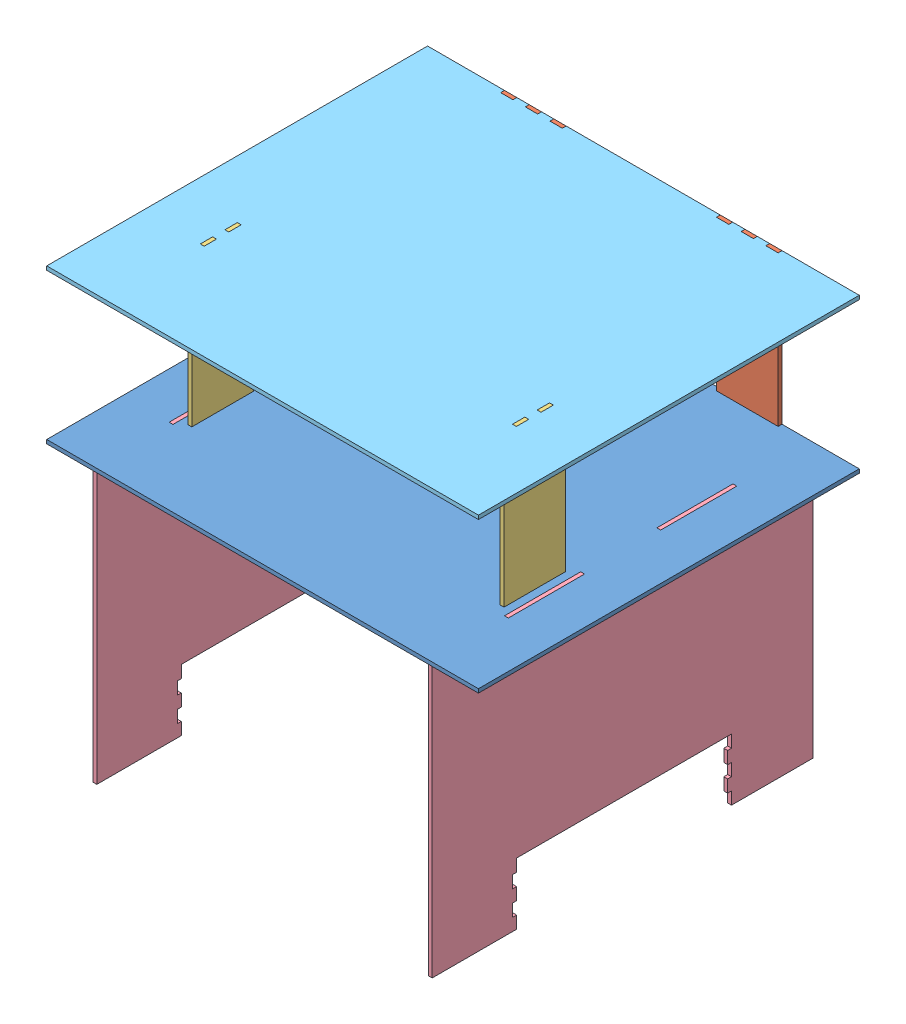
SolidWorks assembly Assem2, configuration Varsayılan. Lengths in mm.
Overall size (560 550 494).
8 component instances, 5 part files, 26 mates.
Components (placement in the parent):
- A_1-1: A_1 [Default] at (-17.2972 -28.734 560) size (560 5 494)
- D_1_prime-4: D_1_prime [Default] at (-157.5107 71.266 313) x (0 -1 0) z (-1 0 0) size (200 5 80)
- D_1_prime-5: D_1_prime [Default] at (122.4893 71.266 313) x (0 1 0) z (1 0 0) size (200 5 80)
- G_1_prime-1: G_1_prime [Default] at (-217.2972 98.766 658.801) x (0 1 0) z (0 0 1) size (200 5 80)
- G_1_prime-3: G_1_prime [Default] at (187.7028 98.766 658.801) x (0 1 0) z (0 0 1) size (200 5 80)
- B_1_prime-1: B_1_prime [Default] at (-237.2972 -306.234 560) size (5 355 494)
- B_1_prime-2: B_1_prime [Default] at (197.7028 -306.234 560) size (5 355 494)
- H_1-1: H_1 [Default] at (-17.2972 166.266 559.9971) size (560 5 494)
Mates (geometry in assembly coordinates):
- Coincident2: coincident aligned: plane of A_1-1 through (-17.2972 -28.734 560) normal (0 -1 0); plane of ? through (182.7028 -28.734 698.801) normal (0 -1 0)
- Coincident3: coincident anti-aligned: plane of A_1-1 through (182.7028 -23.734 634.801) normal (0 0 1); plane of ? through (182.7028 -28.734 634.801) normal (0 0 -1)
- Coincident4: coincident anti-aligned: plane of A_1-1 through (187.7028 -23.734 650.8019) normal (-1 0 0); plane of ? through (187.7028 71.266 674.801) normal (1 0 0)
- Coincident5: coincident aligned: plane of A_1-1 through (-17.2972 -28.734 560) normal (0 -1 0); plane of ? through (-222.2972 -28.734 734.3594) normal (0 -1 0)
- Coincident6: coincident anti-aligned: plane of A_1-1 through (-222.2972 -23.734 682.8038) normal (1 0 0); plane of ? through (-222.2972 71.266 710.3594) normal (-1 0 0)
- Coincident8: coincident anti-aligned: plane of A_1-1 through (-181.5107 -23.734 318) normal (0 0 -1); plane of D_1_prime-4 through (-157.5107 71.266 318) normal (0 0 1)
- Coincident9: coincident aligned: plane of A_1-1 through (-17.2972 -28.734 560) normal (0 -1 0); plane of D_1_prime-4 through (-117.5107 -28.734 318) normal (0 -1 0)
- Coincident10: coincident anti-aligned: plane of A_1-1 through (-117.5107 -23.734 318) normal (-1 0 0); plane of D_1_prime-4 through (-117.5107 171.266 318) normal (1 0 0)
- Coincident11: coincident anti-aligned: plane of A_1-1 through (82.4893 -23.734 318) normal (0 0 -1); plane of D_1_prime-5 through (122.4893 71.266 318) normal (0 0 1)
- Coincident12: coincident aligned: plane of A_1-1 through (-17.2972 -28.734 560) normal (0 -1 0); plane of D_1_prime-5 through (146.4893 -28.734 318) normal (0 -1 0)
- Coincident13: coincident anti-aligned: plane of A_1-1 through (162.4893 -23.734 318) normal (-1 0 0); plane of D_1_prime-5 through (162.4893 -28.734 318) normal (1 0 0)
- Coincident28: coincident anti-aligned: plane of A_1-1 through (182.7028 -23.734 634.801) normal (0 0 1); plane of G_1_prime-3 through (182.7028 -28.734 634.801) normal (0 0 -1)
- Coincident29: coincident anti-aligned: plane of A_1-1 through (187.7028 -23.734 682.8038) normal (-1 0 0); plane of G_1_prime-3 through (187.7028 98.766 658.801) normal (1 0 0)
- Coincident30: coincident aligned: plane of A_1-1 through (-17.2972 -28.734 560) normal (0 -1 0); plane of G_1_prime-3 through (182.7028 -28.734 634.801) normal (0 -1 0)
- Coincident31: coincident anti-aligned: plane of A_1-1 through (-217.2972 -23.734 634.801) normal (0 0 1); plane of G_1_prime-1 through (-222.2972 -28.734 634.801) normal (0 0 -1)
- Coincident32: coincident anti-aligned: plane of A_1-1 through (-217.2972 -23.734 666.8029) normal (-1 0 0); plane of G_1_prime-1 through (-217.2972 98.766 658.801) normal (1 0 0)
- Coincident33: coincident aligned: plane of A_1-1 through (-17.2972 -28.734 560) normal (0 -1 0); plane of G_1_prime-1 through (-222.2972 -28.734 666.801) normal (0 -1 0)
- Coincident34: coincident anti-aligned: plane of A_1-1 through (-232.2972 -23.734 609.4) normal (-1 0 0); plane of B_1_prime-1 through (-232.2972 -306.234 560) normal (1 0 0)
- Coincident35: coincident anti-aligned: plane of A_1-1 through (-237.2972 -23.734 609.4) normal (0 0 1); plane of B_1_prime-1 through (-232.2972 -23.734 609.4) normal (0 0 -1)
- Coincident36: coincident aligned: plane of A_1-1 through (-17.2972 -23.734 560) normal (0 1 0); plane of B_1_prime-1 through (-232.2972 -23.734 708.2) normal (0 1 0)
- Coincident37: coincident anti-aligned: plane of A_1-1 through (202.7028 -23.734 708.2) normal (0 0 -1); plane of B_1_prime-2 through (202.7028 -23.734 708.2) normal (0 0 1)
- Coincident38: coincident anti-aligned: plane of A_1-1 through (197.7028 -23.734 609.4) normal (1 0 0); plane of B_1_prime-2 through (197.7028 -306.234 560) normal (-1 0 0)
- Coincident39: coincident aligned: plane of A_1-1 through (-17.2972 -23.734 560) normal (0 1 0); plane of B_1_prime-2 through (202.7028 -23.734 708.2) normal (0 1 0)
- Coincident43: coincident: plane of G_1_prime-3 through (182.7028 98.766 658.801) normal (-1 0 0); plane of H_1-1 through (182.7028 171.266 666.8) normal (1 0 0)
- Coincident44: coincident: plane of G_1_prime-1 through (-222.2972 166.266 682.801) normal (0 0 1); plane of H_1-1 through (-217.2972 171.266 682.801) normal (0 0 -1)
- Coincident45: coincident anti-aligned: plane of G_1_prime-1 through (-222.2972 166.266 682.801) normal (0 1 0); plane of H_1-1 through (-17.2972 166.266 559.9971) normal (0 -1 0)
